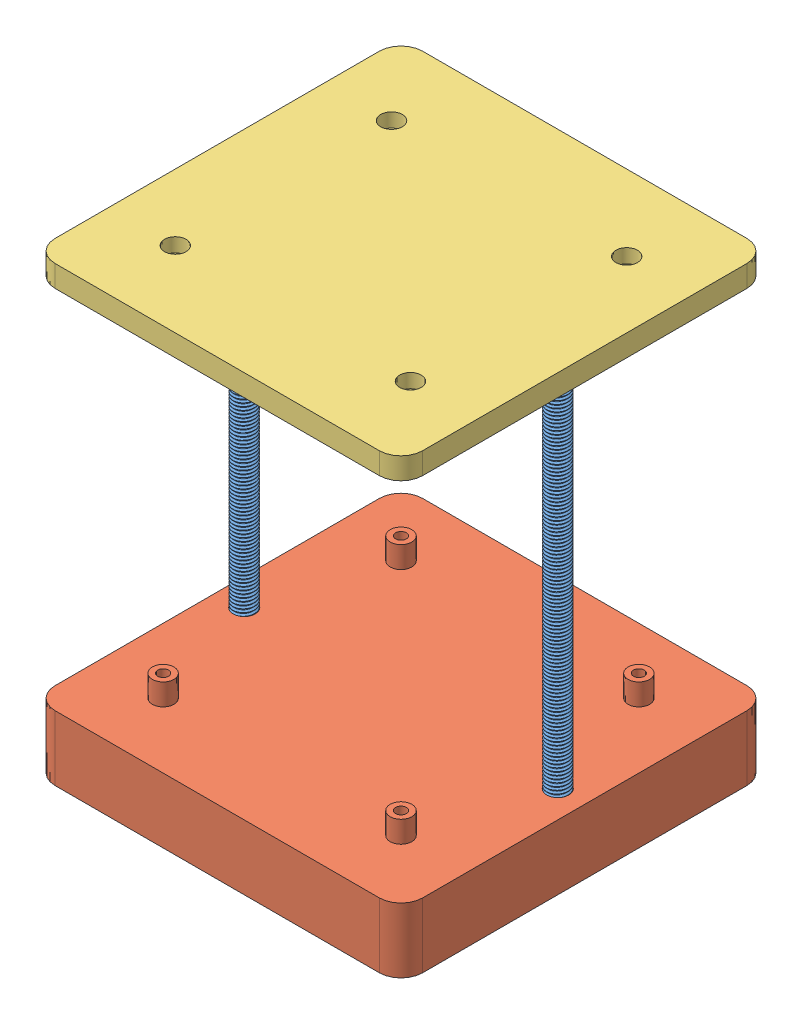
SolidWorks assembly frame_assembly, configuration Default. Lengths in mm.
Overall size (170.01 209.08 170.01).
4 component instances, 3 part files, 24 mates.
Components (placement in the parent):
- threaded_rod-1: threaded_rod [Default] at (201.4153 -103.6108 177.958) x (-0.899129 0 -0.437683) z (0.437683 0 -0.899129) size (11.55 201.64 10.23)
- threaded_rod-2: threaded_rod [Default] at (56.4153 -103.6108 177.958) x (-0.46348 0 -0.886107) z (0.886107 0 -0.46348) size (11.55 201.64 10.23)
- base-2: base [Default] at (213.9153 -108.6108 262.958) x (0 0 -1) z (1 0 0) size (170 40 170)
- top_plate-1: top_plate [Default] at (43.9071 100.471 92.9522) x (1 0 0) z (0 0 -1) size (170 20 170)
Mates (geometry in assembly coordinates):
- Concentric1: concentric anti-aligned: circle of gearbox_back_cover-1; circle of center_gear-1
- Coincident2: coincident: point of gearbox_back_cover-1; point of center_gear-1
- Concentric2: concentric aligned: circle of gearbox_back_cover-1; circle of nut_gear-1
- Concentric3: concentric anti-aligned: circle of gearbox_back_cover-1; circle of nut_gear-2
- Concentric4: concentric anti-aligned: circle of gearbox_back_cover-1; circle of gearbox_cover-1
- Coincident4: coincident anti-aligned: plane of gearbox_back_cover-1 through (56.4153 104.471 177.958) normal (0 1 0); plane of gearbox_cover-1 through (56.4107 104.471 177.9457) normal (0 -1 0)
- Coincident5: coincident anti-aligned: plane of nut_gear-2 through (201.4153 116.471 177.958) normal (0 1 0); plane of gearbox_cover-1 through (201.4107 116.471 177.9457) normal (0 -1 0)
- Coincident6: coincident anti-aligned: plane of nut_gear-1 through (56.4153 116.471 177.958) normal (0 1 0); plane of gearbox_cover-1 through (201.4107 116.471 177.9457) normal (0 -1 0)
- Concentric5: concentric anti-aligned: circle of nut_gear-2; circle of M10 nut-2
- Parallel1: parallel anti-aligned: plane of nut_gear-2 through (198.5474 112.471 170.4897) normal (0.358482 0 0.933537); plane of M10 nut-2 through (193.7869 104.471 171.7822) normal (-0.358482 0 -0.933537)
- Coincident8: coincident anti-aligned: plane of nut_gear-2 through (201.4153 112.471 177.958) normal (0 -1 0); plane of M10 nut-2 through (201.4153 112.471 177.958) normal (0 1 0)
- Concentric6: concentric anti-aligned: circle of nut_gear-1; circle of M10 nut-1
- Parallel2: parallel anti-aligned: plane of nut_gear-1 through (49.679 112.471 173.6425) normal (0.842029 0 0.539433); plane of M10 nut-1 through (46.6108 104.471 177.505) normal (-0.842029 0 -0.539433)
- Coincident10: coincident anti-aligned: plane of nut_gear-1 through (56.4153 112.471 177.958) normal (0 -1 0); plane of M10 nut-1 through (56.4153 112.471 177.958) normal (0 1 0)
- Concentric7: concentric aligned: circle of M10 nut-2; circle of threaded_rod-1
- Concentric8: concentric aligned: circle of M10 nut-1; circle of threaded_rod-2
- Concentric9: concentric aligned: circle of threaded_rod-2; circle of base-2
- Concentric10: concentric aligned: circle of threaded_rod-1; circle of base-2
- Coincident11: coincident anti-aligned: plane of threaded_rod-2 through (56.4153 -103.6108 177.958) normal (0 -1 0); plane of base-2 through (56.4153 -103.6108 177.958) normal (0 1 0)
- Coincident12: coincident anti-aligned: plane of threaded_rod-1 through (201.4153 -103.6108 177.958) normal (0 -1 0); plane of base-2 through (201.4153 -103.6108 177.958) normal (0 1 0)
- Parallel3: parallel aligned: line of gearbox_back_cover-1 through (84.5403 100.471 132.958) axis (1 0 0); line of gearbox_cover-1 through (56.4107 104.471 132.9457) axis (1 0 0)
- Concentric15: concentric aligned: circle of gearbox_back_cover-1; circle of top_plate-1
- Parallel4: parallel aligned: line of gearbox_cover-1 through (56.4107 104.471 132.9457) axis (1 0 0); line of top_plate-1 through (53.9071 100.471 92.9522) axis (1 0 0)
- Coincident15: coincident anti-aligned: plane of gearbox_back_cover-1 through (56.4153 100.471 177.958) normal (0 -1 0); plane of top_plate-1 through (43.9071 100.471 92.9522) normal (0 1 0)
